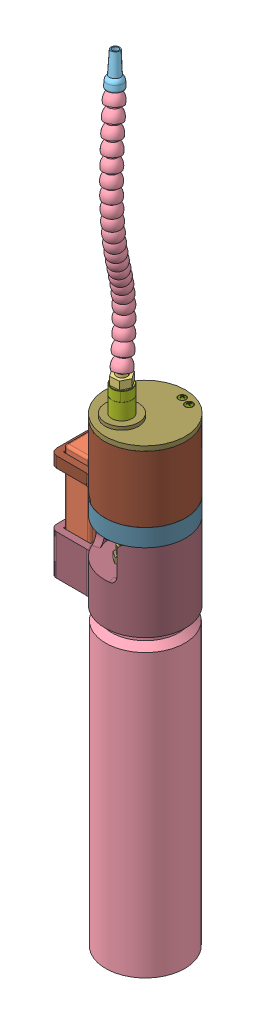
SolidWorks assembly _Robocup_Assembly_Water_Bottle_, configuration Default. Lengths in mm.
Overall size (108.2 756.21 103.62).
85 component instances, 35 part files, 75 mates.
Components (placement in the parent):
- SF3218MG Servo-1: SF3218MG Servo [Default] at (-17.653 -62.7888 -19.9) size (54.86 45.72 19.05)
- Servo gear 30t-1: Servo gear 30t [Default] at (-7.993 -20.4688 -10.375) x (-0.381225 0 -0.924482) z (0 1 0) size (25.51 25.6 6)
- Coolant Pipe.stp-1: Coolant Pipe.stp [Default] at (-8.06 46.6882 14.01) x (0.568385 0 0.822762) z (-0.822762 0 0.568385) size (74.23 300.91 26.18)
  - Coolant Bolt.stp-1: Coolant Bolt.stp [Default] x (-1 0 0) z (0 0 1) size (17.61 27.5 15.25)
  - Connectors.stp-1: Connectors.stp [Default] at (-2.2835 3.6671 -0.0362) x (-0.321951 -0.100327 -0.941426) z (0.285439 -0.958386 0.00452) size (18.3 18.3 20)
  - Connectors.stp-2: Connectors.stp [Default] at (-0.9485 62.1668 -0.2193) x (0.834188 -0.338799 0.435138) z (-0.378337 -0.925657 0.00458) size (18.3 18.3 20)
  - Connectors.stp-3: Connectors.stp [Default] at (-7.0218 39.1054 -0.1142) x (0.974617 -0.052931 0.217534) z (-0.054998 -0.99848 0.003454) size (18.3 18.3 20)
  - Connectors.stp-4: Connectors.stp [Default] at (-7.018 27.1423 -0.0887) x (-0.288884 -0.031731 -0.956838) z (0.11095 -0.993826 -0.00054) size (18.3 18.3 20)
  - Connectors.stp-5: Connectors.stp [Default] at (10.0914 83.4503 -0.3173) x (0.525964 -0.304704 -0.794051) z (-0.497138 -0.867664 0.003658) size (18.3 18.3 20)
  - Connectors.stp-6: Connectors.stp [Default] at (4.2645 72.9625 -0.2712) x (0.886562 -0.462353 0.015441) z (-0.462461 -0.88663 0.004202) size (18.3 18.3 20)
  - Connectors.stp-7: Connectors.stp [Default] at (-4.9174 50.8742 -0.1644) x (0.803108 -0.192004 0.56405) z (-0.235547 -0.971852 0.004557) size (18.3 18.3 20)
  - Connectors.stp-8: Connectors.stp [Default] at (16.0513 93.8656 -0.3564) x (0.86534 -0.495122 -0.077724) z (-0.496415 -0.86808 0.003062) size (18.3 18.3 20)
  - Connectors.stp-9: Connectors.stp [Default] at (35.5838 137.5772 -0.4345) x (0.770438 -0.236558 0.592002) z (-0.293738 -0.955886 0.000312) size (18.3 18.3 20)
  - Connectors.stp-10: Connectors.stp [Default] at (38.4122 149.228 -0.4322) x (0.672162 -0.141658 -0.726727) z (-0.20668 -0.978409 -0.000445) size (18.3 18.3 20)
  - Connectors.stp-11: Connectors.stp [Default] at (31.7619 126.2108 -0.4277) x (0.912958 -0.361121 0.189996) z (-0.368012 -0.929821 0.001063) size (18.3 18.3 20)
  - Connectors.stp-12: Connectors.stp [Default] at (21.8052 104.3949 -0.3882) x (-0.461711 0.244191 -0.852756) z (-0.471034 -0.882112 0.002437) size (18.3 18.3 20)
  - Connectors.stp-13: Connectors.stp [Default] at (-5.2287 15.2947 -0.0801) x (0.757626 0.173214 -0.629285) z (0.225426 -0.974255 0.003232) size (18.3 18.3 20)
  - Connectors.stp-14: Connectors.stp [Default] at (27.1083 115.1559 -0.4121) x (0.901968 -0.4265 -0.067469) z (-0.427365 -0.904078 0.001774) size (18.3 18.3 20)
  - Coolant Pipe Nozzle.stp-1: Coolant Pipe Nozzle.stp [Default] at (27.898 246.6708 -0.2231) x (-0.153795 -0.02183 0.987862) z (0.098368 -0.995128 -0.006677) size (15 15 30)
  - Connectors.stp-15: Connectors.stp [Default] at (40.4307 185.0487 -0.3789) x (0.938856 0.053217 -0.340172) z (0.055817 -0.998439 -0.002147) size (18.3 18.3 20)
  - Connectors.stp-16: Connectors.stp [Default] at (39.2092 196.9799 -0.3507) x (0.937442 0.118696 -0.327281) z (0.124773 -0.992182 -0.002445) size (18.3 18.3 20)
  - Connectors.stp-17: Connectors.stp [Default] at (40.784 173.0623 -0.4029) x (0.972219 -0.02226 -0.233011) z (-0.023301 -0.999727 -0.001718) size (18.3 18.3 20)
  - Connectors.stp-18: Connectors.stp [Default] at (40.1447 161.0902 -0.4212) x (0.882181 -0.100002 -0.460169) z (-0.113225 -0.993569 -0.001143) size (18.3 18.3 20)
  - Connectors.stp-19: Connectors.stp [Default] at (31.9646 232.2183 -0.2574) x (0.793284 0.199128 0.575369) z (0.245233 -0.969461 -0.002594) size (18.3 18.3 20)
  - Connectors.stp-20: Connectors.stp [Default] at (37.2637 208.8167 -0.3201) x (0.26581 0.051415 -0.962653) z (0.180811 -0.983514 -0.002604) size (18.3 18.3 20)
  - Connectors.stp-21: Connectors.stp [Default] at (28.861 243.8093 -0.2266) x (0.725081 0.197806 0.659645) z (0.26534 -0.964151 -0.002545) size (18.3 18.3 20)
  - Connectors.stp-22: Connectors.stp [Default] at (34.7978 220.5587 -0.2886) x (0.975424 0.217793 -0.033387) z (0.217828 -0.975984 -0.002632) size (18.3 18.3 20)
- Arduino Nano.STEP-1: Arduino Nano.STEP [Default] at (17.196 -13.0397 29.7784) x (0 -1 0) z (1 0 0) size (44.28 18 13.68)
  - ATMEGA328P-AU.STEP.STEP-1: ATMEGA328P-AU.STEP.STEP [Default] at (19.8219 24.4243 4.0882) x (-0.707107 -0.707107 0) z (0 0 1) size (9 9 1.2)
    - ATMEGA328P-AU--3DModel-STEP-56544.step.STEP.STEP.STEP.STEP-1: ATMEGA328P-AU--3DModel-STEP-56544.step.STEP.STEP.STEP.STEP [Default] at (2.8163 4.1 0.6768) x (1 0 0) z (0 -1 0) size (9 1.2 9)
  - Arduino Nano.STEP-1: Arduino Nano.STEP [Default] at (8.8551 11.9484 0) size (43.18 18 6.8)
  - Mini USB.STEP-1: Mini USB.STEP [Default] at (8.5451 19.5727 4.14) size (9.5 9.7 3.9)
  - CSTCE Crystal.STEP-1: CSTCE Crystal.STEP [Default] at (25.8562 23.1047 4.15) x (0.707107 -0.707107 0) z (0 0 1) size (3.2 1.35 0.71)
  - 2Pin Tactile Switch 6x3.6.STEP-1: 2Pin Tactile Switch 6x3.6.STEP [Default] at (30.7142 19.8184 4.14) x (0 1 0) z (0 0 1) size (7.9 3.6 2.2)
  - 0603 Resistor.STEP-1: 0603 Resistor.STEP [Default] at (34.4251 22.4184 4.14) size (1.6 0.8 0.5)
  - 0603 Resistor.STEP-2: 0603 Resistor.STEP [Default] at (34.4251 20.7184 4.14) size (1.6 0.8 0.5)
  - 0603 Resistor.STEP-3: 0603 Resistor.STEP [Default] at (34.4251 18.9184 4.14) size (1.6 0.8 0.5)
  - 0603 Resistor.STEP-4: 0603 Resistor.STEP [Default] at (34.4251 17.2184 4.14) size (1.6 0.8 0.5)
  - Blue LED.STEP-1: Blue LED.STEP [Default] at (37.0251 22.4184 4.14) size (1.6 0.8 0.6)
  - Green LED.STEP-1: Green LED.STEP [Default] at (37.0251 20.7184 4.14) size (1.6 0.8 0.6)
  - Red LED.STEP-1: Red LED.STEP [Default] at (37.0251 18.9184 4.14) size (1.6 0.8 0.6)
  - Blue LED.STEP-2: Blue LED.STEP [Default] at (37.0251 17.2184 4.14) size (1.6 0.8 0.6)
  - Header 2x3.STEP-1: Header 2x3.STEP [Default] at (45.6765 17.0321 4.14) x (0 1 0) z (0 0 1) size (7.62 5.07 10)
  - SOT89.STEP-1: SOT89.STEP [Default] at (38.4751 17.3184 0.94) x (0 1 0) z (0 0 1) size (6.5 7.1 1.6)
  - 1206 Tantalum.STEP-1: 1206 Tantalum.STEP [Default] at (38.6251 22.3684 2.54) x (-1 0 0) z (0 0 -1) size (3.2 1.6 1.5)
  - 0603 Resistor.STEP-5: 0603 Resistor.STEP [Default] at (38.4251 24.9684 2.54) x (-1 0 0) z (0 0 -1) size (1.6 0.8 0.5)
  - 0603 Capacitor.STEP-1: 0603 Capacitor.STEP [Default] at (35.0338 14.4684 2.54) x (-1 0 0) z (0 0 -1) size (1.6 0.8 0.7)
  - 1206 Tantalum.STEP-2: 1206 Tantalum.STEP [Default] at (7.6451 24.3684 2.54) x (1 0 0) z (0 0 -1) size (3.2 1.6 1.5)
  - 0603 Capacitor.STEP-2: 0603 Capacitor.STEP [Default] at (6.9059 22.4745 2.54) x (-1 0 0) z (0 0 -1) size (1.6 0.8 0.7)
  - 0603 Capacitor.STEP-3: 0603 Capacitor.STEP [Default] at (17.8451 14.0245 2.54) x (-1 0 0) z (0 0 -1) size (1.6 0.8 0.7)
  - 0603 Capacitor.STEP-4: 0603 Capacitor.STEP [Default] at (17.8451 15.0767 2.54) x (-1 0 0) z (0 0 -1) size (1.6 0.8 0.7)
  - 0603 Capacitor.STEP-5: 0603 Capacitor.STEP [Default] at (25.3451 21.2855 2.54) x (-1 0 0) z (0 0 -1) size (1.6 0.8 0.7)
  - 0603 Resistor.STEP-6: 0603 Resistor.STEP [Default] at (23.8451 15.8601 2.54) x (-1 0 0) z (0 0 -1) size (1.6 0.8 0.5)
  - 0603 Resistor.STEP-7: 0603 Resistor.STEP [Default] at (23.8451 14.4709 2.54) x (-1 0 0) z (0 0 -1) size (1.6 0.8 0.5)
  - CSTCE Crystal.STEP-2: CSTCE Crystal.STEP [Default] at (13.1731 14.7184 2.53) x (-1 0 0) z (0 0 -1) size (3.2 1.35 0.71)
  - SOIC16.STEP-1: SOIC16.STEP [Default] at (16.6451 19.5642 2.54) x (-1 0 0) z (0 0 -1) size (10.2 6 1.5)
- 5V Battery-1: 5V Battery [Default] at (-51.308 -148.9027 0) x (-1 0 0) z (0 0 -1) size (24.89 102.87 26.92)
- 51235K107_Push-to-Connect Tube Fitting with Universal Thread-1: 51235K107_Push-to-Connect Tube Fitting with Universal Thread [51235K107] at (-7.62 -99.2427 13.1982) x (0 -1 0) z (-0.427129 0 -0.904191) size (19.14 14.66 12.7)
- 51235K107_Push-to-Connect Tube Fitting with Universal Thread-2: 51235K107_Push-to-Connect Tube Fitting with Universal Thread [51235K107] at (-7.62 -140.1427 13.1982) x (0 1 0) z (0.852121 0 -0.523345) size (19.14 14.66 12.7)
- Water Bottle-1: Water Bottle [Default] at (0 -432.1127 0) size (74.93 304.8 74.93)
- Robocup_Shaft-1: Robocup_Shaft [Default] at (-8.06 -77.47 14.01) x (0.635001 0 0.772511) z (-0.772511 0 0.635001) size (20.32 97.79 20.32)
- Robocup_Bushing-3: Robocup_Bushing [6383K234] at (-8.06 -67.3013 14.01) x (-0.988739 0 0.149647) z (0 -1 0) size (31.75 31.75 11.13)
- Robocup_Straw_Adapter-1: Robocup_Straw_Adapter [Default] at (-8.06 17.8372 14.01) x (0 1 0) z (-0.635001 0 -0.772511) size (24.57 19.05 19.05)
- Robocup_Spacer-1: Robocup_Spacer [Default] at (-8.06 -60.9386 14.01) x (0.976941 0 0.21351) z (-0.21351 0 0.976941) size (19.05 40.47 19.05)
- Robocup_Shaft_Collar-1: Robocup_Shaft_Collar [top] at (-8.06 -1.7988 14.01) x (0.448618 0 0.893723) z (0.893723 0 -0.448618) size (19.05 12.32 19.05)
- Robocup_Motor_Mount-1: Robocup_Motor_Mount [Default] at (2.54 -40.9448 -9.95) x (0 0 -1) z (1 0 0) size (71.12 62.53 65.19)
- Robocup_Motor_Shield-1: Robocup_Motor_Shield [Default] at (0 -62.5348 0) size (108.2 62.78 76.2)
- Robocup_Motor_Top-2: Robocup_Motor_Top [Default] at origin size (76.2 7.62 76.2)
- Robocup_Lid_Water_Bottle-1: Robocup_Lid_Water_Bottle [Default] at (0 -152.7127 0) size (108.2 74.02 76.2)
- Robocup_Motor_Base-2: Robocup_Motor_Base [Default] at (0 -106.9848 0) size (76.2 51.17 76.2)
- Robocup_Gear-2: Robocup_Gear [Default] at (-8.06 -20.4678 14.01) x (-0.387559 0 -0.921845) z (0 1 0) size (25.51 25.6 6.35)
- 91802A146_Passivated 18-8 Stainless Steel Phillips Oval Head Screws-1: 91802A146_Passivated 18-8 Stainless Steel Phillips Oval Head Screws [91802A146] at (-21.59 -35.7677 -15.201) x (0 -1 0) z (-0.546944 0 0.837169) size (10.75 6.65 6.65)
- 91802A146_Passivated 18-8 Stainless Steel Phillips Oval Head Screws-2: 91802A146_Passivated 18-8 Stainless Steel Phillips Oval Head Screws [91802A146] at (13.65 -0.3175 -27.73) x (0 -1 0) z (-0.520208 0 0.85404) size (10.75 6.65 6.65)
- 91802A146_Passivated 18-8 Stainless Steel Phillips Oval Head Screws-3: 91802A146_Passivated 18-8 Stainless Steel Phillips Oval Head Screws [91802A146] at (26.67 -35.7677 -5.549) x (0 -1 0) z (-0.546944 0 0.837169) size (10.75 6.65 6.65)
- 91802A146_Passivated 18-8 Stainless Steel Phillips Oval Head Screws-4: 91802A146_Passivated 18-8 Stainless Steel Phillips Oval Head Screws [91802A146] at (22.6869 -16.0655 3.182) x (1 0 0) z (0 -0.752403 0.658703) size (10.75 6.65 6.65)
- 91802A146_Passivated 18-8 Stainless Steel Phillips Oval Head Screws-5: 91802A146_Passivated 18-8 Stainless Steel Phillips Oval Head Screws [91802A146] at (26.67 -35.7677 -15.201) x (0 -1 0) z (0 0 1) size (10.75 6.65 6.65)
- 91802A146_Passivated 18-8 Stainless Steel Phillips Oval Head Screws-6: 91802A146_Passivated 18-8 Stainless Steel Phillips Oval Head Screws [91802A146] at (4.445 -63.4873 -30.48) x (0 -1 0) z (0 0 1) size (10.75 6.65 6.65)
- 91802A146_Passivated 18-8 Stainless Steel Phillips Oval Head Screws-7: 91802A146_Passivated 18-8 Stainless Steel Phillips Oval Head Screws [91802A146] at (-4.445 -63.4873 -30.48) x (0 -1 0) z (-0.546944 0 0.837169) size (10.75 6.65 6.65)
- 91802A146_Passivated 18-8 Stainless Steel Phillips Oval Head Screws-8: 91802A146_Passivated 18-8 Stainless Steel Phillips Oval Head Screws [91802A146] at (-21.59 -35.7677 -5.549) x (0 -1 0) z (0 0 1) size (10.75 6.65 6.65)
- 91802A146_Passivated 18-8 Stainless Steel Phillips Oval Head Screws-9: 91802A146_Passivated 18-8 Stainless Steel Phillips Oval Head Screws [91802A146] at (4.76 -0.3175 -30.27) x (0 -1 0) z (-0.999956 0 -0.009425) size (10.75 6.65 6.65)
- 91802A146_Passivated 18-8 Stainless Steel Phillips Oval Head Screws-11: 91802A146_Passivated 18-8 Stainless Steel Phillips Oval Head Screws [91802A146] at (-13.7901 -6.2438 16.8863) x (0.893723 0 -0.448618) z (-0.414893 -0.380394 -0.826538) size (10.75 6.65 6.65)
- 90480A007_Low-Strength Steel Hex Nut-1: 90480A007_Low-Strength Steel Hex Nut [90480A007] at (13.65 -3.9291 -27.73) x (0.931587 0 0.363518) z (-0.363518 0 0.931587) size (7.94 3.39 9.17)
- 90480A007_Low-Strength Steel Hex Nut-2: 90480A007_Low-Strength Steel Hex Nut [90480A007] at (4.76 -3.9291 -30.27) x (0.772389 0 -0.635149) z (0.635149 0 0.772389) size (7.94 3.39 9.17)
- 90480A007_Low-Strength Steel Hex Nut-3: 90480A007_Low-Strength Steel Hex Nut [90480A007] at (4.445 -67.0989 -30.48) size (7.94 3.39 9.17)
- 90480A007_Low-Strength Steel Hex Nut-4: 90480A007_Low-Strength Steel Hex Nut [90480A007] at (-4.445 -67.0989 -30.48) size (7.94 3.39 9.17)
Mates (geometry in assembly coordinates):
- Concentric6: concentric aligned: cylinder of robocup hollow shaft midfi-1 through (-8.06 20.32 14.01) axis (0 -1 0) radius 6.096; cylinder of Robocup bushing-3 through (-8.06 -72.0638 14.01) axis (0 -1 0) radius 6.35
- Concentric7: concentric anti-aligned: cylinder of robocup hollow shaft midfi-1 through (-8.06 20.32 14.01) axis (0 -1 0) radius 6.096; cylinder of shaft to fourth npt female midfi-1 through (-8.06 7.62 14.01) axis (0 1 0) radius 6.223
- Coincident13: coincident anti-aligned: plane of robocup hollow shaft midfi-1 through (-14.0482 20.32 17.2883) normal (0.635001 0 0.772511); plane of shaft to fourth npt female midfi-1 through (-12.7908 7.62 16.2547) normal (-0.635001 0 -0.772511)
- Coincident15: coincident anti-aligned: plane of robocup hollow shaft midfi-1 through (-8.06 20.32 14.01) normal (0 1 0); plane of shaft to fourth npt female midfi-1 through (-8.06 20.32 14.01) normal (0 -1 0)
- Concentric10: concentric aligned: cylinder of robocup hollow shaft midfi-1 through (-8.06 20.32 14.01) axis (0 -1 0) radius 6.096; cylinder of Robocup_Spacer-1 through (-8.06 -20.4678 14.01) axis (0 -1 0) radius 9.525
- Concentric12: concentric anti-aligned: cylinder of robocup hollow shaft midfi-1 through (-8.06 20.32 14.01) axis (0 -1 0) radius 6.096; cylinder of Robocup_Shaft_Collar-1 through (-8.06 -6.2438 14.01) axis (0 1 0) radius 9.525
- Concentric55: concentric aligned: circle of shaft to fourth npt female-1; circle of Coolant Pipe.stp-1/Coolant Bolt.stp-1
- Coincident109: coincident anti-aligned: plane of shaft to fourth npt female midfi-1 through (-8.06 32.1882 14.01) normal (0 1 0); plane of Coolant Pipe.stp-1/Coolant Bolt.stp-1 through (-8.06 32.1882 14.01) normal (0 -1 0)
- Coincident115: coincident anti-aligned: plane of Robocup Top Plate lowfi-2 through (0 0 0) normal (0 -1 0); plane of Robocup_Motor_Mount-1 through (0 0 0) normal (0 1 0)
- Coincident117: coincident anti-aligned: plane of Robocup_Motor_Shield-1 through (0 0 0) normal (0 1 0); plane of Robocup Top Plate lowfi-2 through (0 0 0) normal (0 -1 0)
- Coincident127: coincident anti-aligned: plane of Robocup bushing-3 through (-9.2963 -60.9386 5.8417) normal (0 1 0); plane of Robocup_Spacer-1 through (-8.06 -60.9386 14.01) normal (0 -1 0)
- Coincident131: coincident anti-aligned: plane of Robocup_Motor_Mount-1 through (21.336 22.5049 2.21) normal (-1 0 0); plane of Arduino Nano.STEP-1/Arduino Nano.STEP-1 through (21.336 -21.8948 17.83) normal (1 0 0)
- Coincident133: coincident anti-aligned: plane of Robocup_Motor_Mount-1 through (21.336 22.5049 1.21) normal (0 0 1); plane of Arduino Nano.STEP-1/Arduino Nano.STEP-1 through (21.336 -18.0848 1.21) normal (0 0 -1)
- Parallel1: parallel anti-aligned: plane of Robocup_Motor_Shield-1 through (0 -62.5348 0) normal (1 0 0); plane of Robocup_Motor_Mount-1 through (-29.4704 -62.5348 0) normal (-1 0 0)
- Coincident136: coincident aligned: plane of Robocup Top Plate lowfi-2 through (0 0 0) normal (0 0 1)
- Coincident137: coincident aligned: plane of Robocup Top Plate lowfi-2 through (0 0 0) normal (1 0 0)
- Coincident138: coincident aligned: plane of Robocup Top Plate lowfi-2 through (0 0 0) normal (0 1 0)
- Concentric77: concentric anti-aligned: cylinder of Robocup_Motor_Mount-1 through (0 -62.5348 0) axis (0 1 0) radius 35.56; cylinder of Robocup_Motor_Shield-1 through (0 0 0) axis (0 -1 0) radius 38.1
- Parallel6: parallel aligned: plane of Robocup_Motor_Mount-1 through (2.54 -40.9448 -9.95) normal (1 0 0)
- Concentric78: concentric aligned: cylinder of SF3218MG Servo-1 through (-7.993 39.4275 -10.375) axis (0 -1 0) radius 3.81; cylinder of Servo gear 30t-1 through (-7.993 11.0983 -10.375) axis (0 -1 0) radius 3.85
- Coincident165: coincident anti-aligned: plane of SF3218MG Servo-1 through (-17.653 -62.7888 -19.9) normal (0 0 -1); plane of Robocup_Motor_Mount-1 through (-17.78 -35.8648 -19.9) normal (0 0 1)
- Coincident166: coincident anti-aligned: plane of SF3218MG Servo-1 through (-17.653 -35.8648 -27.7545) normal (0 -1 0); plane of Robocup_Motor_Mount-1 through (2.54 -35.8648 -9.95) normal (0 1 0)
- Coincident168: coincident anti-aligned: plane of SF3218MG Servo-1 through (-17.653 -17.0688 -0.85) normal (0 1 0); plane of Servo gear 30t-1 through (-7.993 -17.0688 -10.375) normal (0 -1 0)
- Concentric79: concentric anti-aligned: cylinder of motorbox lid v10-1 through (0 -152.7127 0) axis (0 -1 0) radius 38.1; cylinder of motorbox bottom low-fi-2 through (0 -186.8158 0) axis (0 1 0) radius 38.1
- Coincident170: coincident aligned: plane of motorbox lid v10-1 through (0 -152.7127 0) normal (1 0 0); plane of motorbox bottom low-fi-2 through (0 -106.9848 0) normal (1 0 0)
- Coincident171: coincident aligned: plane of motorbox lid v10-1 through (0 -152.7127 0) normal (1 0 0)
- Coincident172: coincident aligned: plane of motorbox lid v10-1 through (0 -152.7127 0) normal (0 0 1)
- Concentric84: concentric anti-aligned: cylinder of Robocup_Motor_Mount-1 through (0 -62.5348 0) axis (0 1 0) radius 35.56; cylinder of motorbox lid v10-1 through (0 -152.7127 0) axis (0 -1 0) radius 38.1
- Coincident175: coincident anti-aligned: plane of Robocup bushing-3 through (-9.664 -64.0628 3.4119) normal (0 -1 0); plane of motorbox bottom low-fi-2 through (-1.0936 -64.0628 1.9012) normal (0 1 0)
- Coincident178: coincident anti-aligned: plane of 5V Battery-1 through (-51.308 -148.9027 0) normal (0 0 -1)
- Coincident180: coincident anti-aligned: plane of 5V Battery-1 through (-63.754 -46.0327 13.462) normal (-1 0 0); plane of motorbox lid v10-1 through (-63.754 -59.2998 13.843) normal (1 0 0)
- Coincident181: coincident anti-aligned: plane of motorbox lid v10-1 through (0 -113.3427 0) normal (0 1 0); plane of motorbox bottom low-fi-2 through (0 -113.3427 0) normal (0 -1 0)
- Coincident182: coincident anti-aligned: plane of motorbox lid v10-1 through (0 -113.3427 0) normal (0 1 0); plane of 51235K107_Push-to-Connect Tube Fitting with Universal Thread-1 through (-7.62 -113.3427 13.1982) normal (0 -1 0)
- Concentric86: concentric anti-aligned: circle of motorbox lid v10-1; cylinder of 51235K107_Push-to-Connect Tube Fitting with Universal Thread-1 through (-7.62 -99.2427 13.1982) axis (0 1 0) radius 5
- Coincident183: coincident anti-aligned: plane of motorbox lid v10-1 through (0 -126.0427 0) normal (0 -1 0); plane of 51235K107_Push-to-Connect Tube Fitting with Universal Thread-2 through (-7.62 -126.0427 13.1982) normal (0 1 0)
- Coincident187: coincident anti-aligned: plane of Robocup_Motor_Mount-1 through (2.54 -61.2648 -9.95) normal (0 1 0); plane of Arduino Nano.STEP-1/Arduino Nano.STEP-1 through (21.336 -61.2648 1.21) normal (0 -1 0)
- Concentric90: concentric aligned: cylinder of robocup hollow shaft midfi-1 through (-8.06 20.32 14.01) axis (0 -1 0) radius 6.096; cylinder of robocup straw gear 30t-2 through (-8.06 -14.4678 14.01) axis (0 -1 0) radius 6.223
- Coincident188: coincident anti-aligned: plane of Robocup_Spacer-1 through (-8.06 -20.4678 14.01) normal (0 1 0); plane of robocup straw gear 30t-2 through (-19.297 -20.4678 19.2561) normal (0 -1 0)
- Coincident190: coincident anti-aligned: plane of Robocup_Motor_Mount-1 through (2.54 -62.5348 -9.95) normal (0 -1 0); plane of motorbox bottom low-fi-2 through (0 -62.5348 0) normal (0 1 0)
- Coincident191: coincident anti-aligned: plane of Robocup_Shaft_Collar-1 through (-8.06 -14.1178 14.01) normal (0 -1 0); plane of robocup straw gear 30t-2 through (-2.7381 -14.1178 24.9065) normal (0 1 0)
- Distance1: distance = 0.635 mm anti-aligned: plane of SF3218MG Servo-1 through (22.733 -62.7888 -0.85) normal (1 0 0); plane of robocup servo mount mid-fi-1 through (23.368 -62.5348 0) normal (-1 0 0)
- Concentric92: concentric aligned: cylinder of Robocup Top Plate lowfi-2 through (13.65 0 -27.73) axis (0 1 0) radius 1.778; circle of 91802A146_Passivated 18-8 Stainless Steel Phillips Oval Head Screws-2
- Coincident193: coincident aligned: plane of Robocup Top Plate lowfi-2 through (0 4.445 0) normal (0 1 0); circle of 91802A146_Passivated 18-8 Stainless Steel Phillips Oval Head Screws-2
- Concentric94: concentric aligned: circle of 91802A146_Passivated 18-8 Stainless Steel Phillips Oval Head Screws-9; circle of Robocup Top Plate midfi-2
- Coincident194: coincident aligned: plane of Robocup Top Plate lowfi-2 through (0 4.445 0) normal (0 1 0); circle of 91802A146_Passivated 18-8 Stainless Steel Phillips Oval Head Screws-9
- Concentric95: concentric anti-aligned: cylinder of Robocup_Motor_Mount-1 through (4.445 -37.1348 -30.48) axis (0 -1 0) radius 2.032; circle of 91802A146_Passivated 18-8 Stainless Steel Phillips Oval Head Screws-6
- Coincident195: coincident aligned: plane of Robocup_Motor_Mount-1 through (2.54 -58.7248 -9.95) normal (0 1 0); circle of 91802A146_Passivated 18-8 Stainless Steel Phillips Oval Head Screws-6
- Concentric96: concentric anti-aligned: cylinder of Robocup_Motor_Mount-1 through (-4.445 -37.1348 -30.48) axis (0 -1 0) radius 2.032; circle of 91802A146_Passivated 18-8 Stainless Steel Phillips Oval Head Screws-7
- Coincident196: coincident aligned: plane of Robocup_Motor_Mount-1 through (2.54 -58.7248 -9.95) normal (0 1 0); circle of 91802A146_Passivated 18-8 Stainless Steel Phillips Oval Head Screws-7
- Concentric97: concentric aligned: cylinder of SF3218MG Servo-1 through (-21.59 -62.7888 -15.201) axis (0 1 0) radius 2.54; circle of 91802A146_Passivated 18-8 Stainless Steel Phillips Oval Head Screws-1
- Coincident197: coincident aligned: plane of SF3218MG Servo-1 through (-17.653 -32.8168 -27.7545) normal (0 1 0); circle of 91802A146_Passivated 18-8 Stainless Steel Phillips Oval Head Screws-1
- Coincident198: coincident aligned: plane of SF3218MG Servo-1 through (-17.653 -32.8168 -27.7545) normal (0 1 0); circle of 91802A146_Passivated 18-8 Stainless Steel Phillips Oval Head Screws-8
- Concentric98: concentric aligned: cylinder of SF3218MG Servo-1 through (-21.59 -62.7888 -5.549) axis (0 1 0) radius 2.54; circle of 91802A146_Passivated 18-8 Stainless Steel Phillips Oval Head Screws-8
- Coincident199: coincident aligned: plane of SF3218MG Servo-1 through (22.733 -32.8168 -27.7545) normal (0 1 0); circle of 91802A146_Passivated 18-8 Stainless Steel Phillips Oval Head Screws-5
- Concentric99: concentric aligned: cylinder of SF3218MG Servo-1 through (26.67 -62.7888 -15.201) axis (0 1 0) radius 2.54; circle of 91802A146_Passivated 18-8 Stainless Steel Phillips Oval Head Screws-5
- Concentric100: concentric aligned: circle of SF3218MG Servo-1; circle of 91802A146_Passivated 18-8 Stainless Steel Phillips Oval Head Screws-3
- Coincident200: coincident aligned: plane of SF3218MG Servo-1 through (22.733 -32.8168 -27.7545) normal (0 1 0); circle of 91802A146_Passivated 18-8 Stainless Steel Phillips Oval Head Screws-3
- Concentric101: concentric aligned: cylinder of Robocup_Motor_Mount-1 through (34.4929 -16.0655 3.182) axis (-1 0 0) radius 1.778; circle of 91802A146_Passivated 18-8 Stainless Steel Phillips Oval Head Screws-4
- Coincident201: coincident aligned: plane of Arduino Nano.STEP-1/Arduino Nano.STEP-1 through (19.736 -21.8948 17.83) normal (-1 0 0); circle of 91802A146_Passivated 18-8 Stainless Steel Phillips Oval Head Screws-4
- Concentric106: concentric anti-aligned: cylinder of Robocup_Shaft_Collar-1 through (-16.5727 -6.2438 18.2831) axis (0.893723 0 -0.448618) radius 1.7145; circle of 91802A146_Passivated 18-8 Stainless Steel Phillips Oval Head Screws-11
- Tangent9: tangent: cylinder of Robocup_Shaft_Collar-1 through (-8.06 -6.2438 14.01) axis (0 1 0) radius 9.525; circle of 91802A146_Passivated 18-8 Stainless Steel Phillips Oval Head Screws-11
- Concentric107: concentric aligned: cylinder of robocup hollow shaft midfi-1 through (-8.06 20.32 14.01) axis (0 -1 0) radius 6.096; cylinder of Robocup Top Plate lowfi-2 through (-8.06 7.62 14.01) axis (0 -1 0) radius 6.35
- Coincident202: coincident anti-aligned: plane of shaft to fourth npt female midfi-1 through (-8.06 7.62 14.01) normal (0 -1 0); plane of Robocup Top Plate lowfi-2 through (-8.06 7.62 14.01) normal (0 1 0)
- Coincident203: coincident anti-aligned: plane of Robocup_Motor_Mount-1 through (2.54 -2.54 -9.95) normal (0 -1 0); plane of 90480A007_Low-Strength Steel Hex Nut-1 through (10.7857 -2.54 -31.3073) normal (0 1 0)
- Coincident204: coincident anti-aligned: plane of Robocup_Motor_Mount-1 through (2.54 -2.54 -9.95) normal (0 -1 0); plane of 90480A007_Low-Strength Steel Hex Nut-2 through (0.2392 -2.54 -29.5191) normal (0 1 0)
- Concentric109: concentric anti-aligned: circle of Robocup Top Plate lowfi-2; circle of 90480A007_Low-Strength Steel Hex Nut-2
- Concentric110: concentric aligned: circle of 91802A146_Passivated 18-8 Stainless Steel Phillips Oval Head Screws-2; circle of 90480A007_Low-Strength Steel Hex Nut-1
- Parallel9: parallel anti-aligned: plane of Robocup_Motor_Mount-1 through (21.9136 -8.89 -35.8592) normal (-0.931587 0 -0.363518); plane of 90480A007_Low-Strength Steel Hex Nut-1 through (16.5143 -2.54 -24.1527) normal (0.931587 0 0.363518)
- Parallel10: parallel anti-aligned: plane of Robocup_Motor_Mount-1 through (1.82 -8.89 -34.2344) normal (0.93625 0 0.351334); plane of 90480A007_Low-Strength Steel Hex Nut-2 through (1.8493 -2.54 -33.8096) normal (-0.93625 0 -0.351334)
- Coincident205: coincident anti-aligned: plane of motorbox bottom low-fi-2 through (0 -65.7098 0) normal (0 -1 0); plane of 90480A007_Low-Strength Steel Hex Nut-4 through (-8.4137 -65.7098 -32.7714) normal (0 1 0)
- Coincident206: coincident anti-aligned: plane of motorbox bottom low-fi-2 through (0 -65.7098 0) normal (0 -1 0); plane of 90480A007_Low-Strength Steel Hex Nut-3 through (0.4763 -65.7098 -32.7714) normal (0 1 0)
- Concentric112: concentric anti-aligned: circle of motorbox bottom low-fi-1; circle of 90480A007_Low-Strength Steel Hex Nut-3
- Concentric113: concentric anti-aligned: circle of motorbox bottom low-fi-1; circle of 90480A007_Low-Strength Steel Hex Nut-4
- Concentric114: concentric aligned: cylinder of motorbox lid v10-1 through (0 -152.7127 0) axis (0 -1 0) radius 38.1; cylinder of Water Bottle-1 through (0 -432.1127 0) axis (0 -1 0) radius 37.465
- Coincident207: coincident anti-aligned: plane of motorbox lid v10-1 through (31.75 -127.3127 0) normal (0 -1 0); plane of Water Bottle-1 through (31.75 -127.3127 0) normal (0 1 0)
